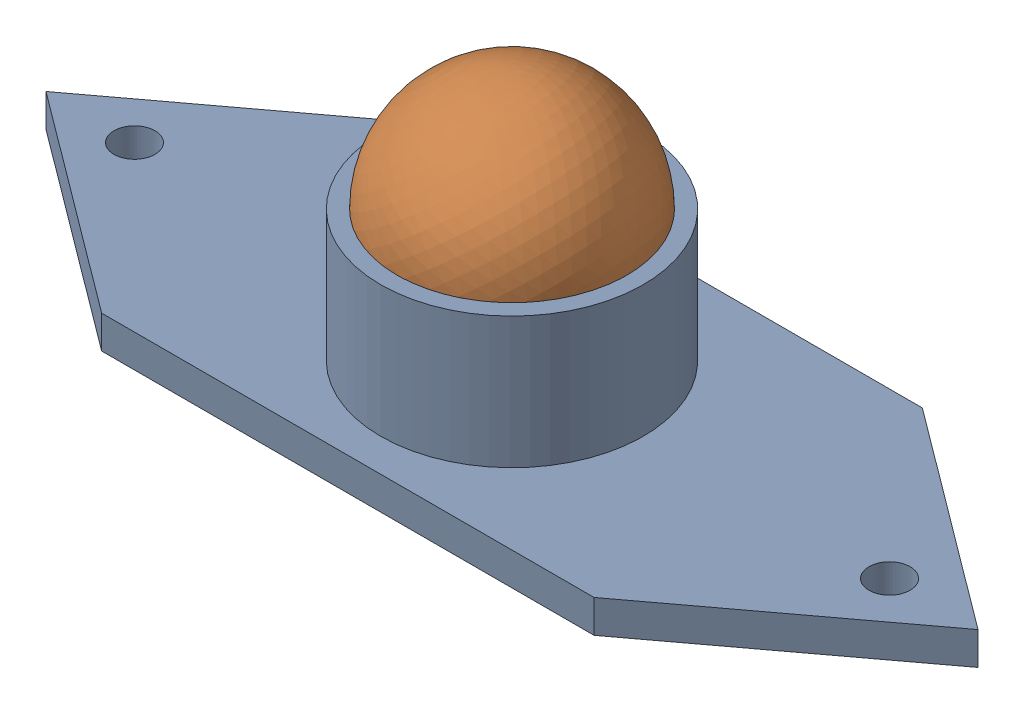
SolidWorks assembly ballbearing_and_mount, configuration Default. Lengths in mm.
Overall size (56.78 21.23 20).
2 component instances, 2 part files, 2 mates.
Components (placement in the parent):
- ballbearing mount-1: ballbearing mount [Default] at (648.003 859.915 1279.6035) size (56.78 10 20)
- ballbearing-1: ballbearing [Default] at (663.003 869.915 1269.6035) x (0.734183 0.597341 -0.322737) z (0.310594 0.127202 0.941993) size (14 14 14)
Mates (geometry in assembly coordinates):
- Concentric1: concentric: cylinder of ballbearing mount-1 through (663.003 869.915 1269.6035) axis (0 -1 0) radius 7; sphere of ballbearing-1
- Tangent1: tangent: circle of ballbearing mount-1; sphere of ballbearing-1
